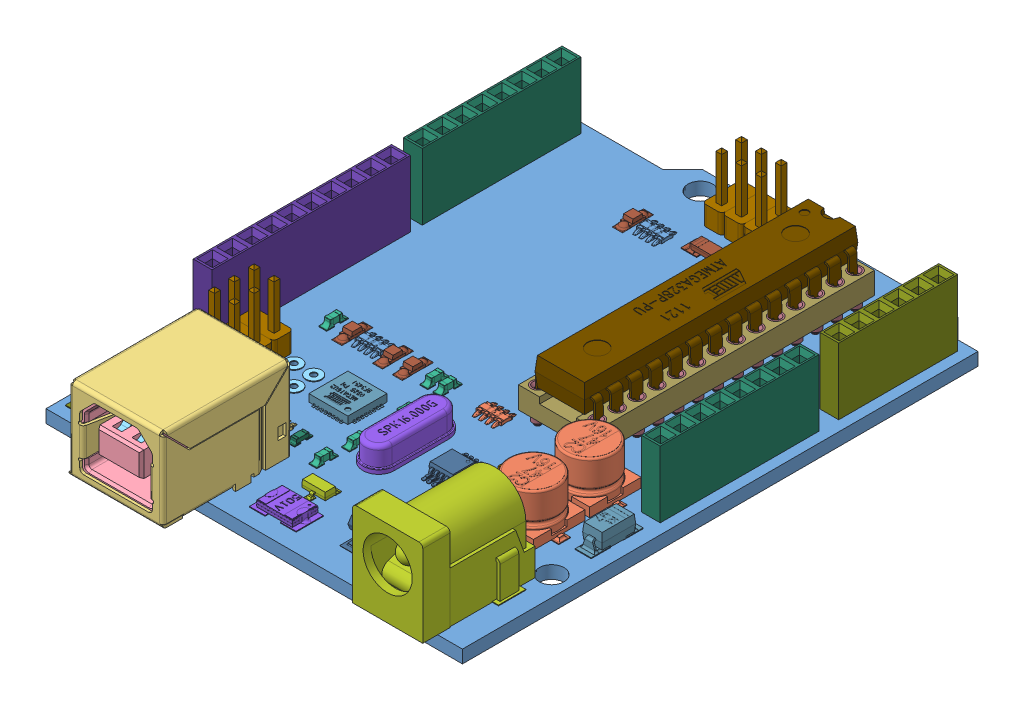
SolidWorks assembly arduino uno, configuration Default. Lengths in mm.
Overall size (53.34 15.25 74.93).
87 component instances, 35 part files, 133 mates.
Components (placement in the parent):
- unoboard blue-1: unoboard blue [Default] at origin size (53.34 1.65 68.58)
- 47uf CAP Dcase-1: 47uf CAP Dcase [Default] at (-9.4141 0 -18.4991) x (0 0 -1) z (1 0 0) size (6.6 5.81 8)
- USB type b-1: USB type b [Default] at (-38.02 0.43 6.35) size (14.34 15.2 16.5)
  - USB SHELL-1: USB SHELL [Default] at origin size (14.34 15.2 16.5)
  - USB core-1: USB core [Default] at origin size (11.3 10.68 15.75)
  - usb top contact-1: usb top contact [Default] at (1.25 6.09 -0.38) size (1 9.67 13.76)
  - usb btm contact-1: usb btm contact [Default] at (1.25 4.41 -0.38) size (1 6.84 11.76)
  - usb btm contact-2: usb btm contact [Default] at (-1.25 4.41 -0.38) size (1 6.84 11.76)
  - usb top contact-2: usb top contact [Default] at (-1.25 6.09 -0.38) size (1 9.67 13.76)
- power jack-1: power jack [Default] at (-7.675 0 1.905) size (11.2 15.2 15.9)
- 47uf CAP Dcase-2: 47uf CAP Dcase [Default] at (-9.4141 0 -25.7132) x (0 0 -1) z (1 0 0) size (6.6 5.81 8)
- crystal-1: crystal [Default] at (-26.162 0 -18.923) x (1 0 0) z (0 0 -1) size (4 5 11)
- 2pin_header__02-1: 2pin_header__02 [Default] at (-46.23 0 -15.75) size (5 11.75 2.54)
- nano - reg-1: nano - reg [Default] at (-17.399 0 -7.747) size (6.5 1.69 8.3)
- led-1: led [Default] at (-34.29 0 -27.94) x (0 0 1) z (-1 0 0) size (4 0.86 1.35)
- 2pin_header__02-2: 2pin_header__02 [Default] at (-30.43 0 -64.91) x (0 0 1) z (-1 0 0) size (5 11.75 2.54)
- dip28-1: dip28 [Default] at (-16.383 1.5 -46.355) x (0 0 -1) z (1 0 0) size (35.48 7.37 10.1)
  - dip28-1: dip28 [Default] at origin size (35.48 2.8 10.1)
  - dip socket pin-1: dip socket pin [Default] at (16.51 2.8 -3.81) size (1.7 7.37 1.7)
  - dip socket pin-2: dip socket pin [Default] at (16.51 2.8 3.81) size (1.7 7.37 1.7)
  - dip socket pin-3: dip socket pin [Default] at (13.97 2.8 -3.81) size (1.7 7.37 1.7)
  - dip socket pin-4: dip socket pin [Default] at (13.97 2.8 3.81) size (1.7 7.37 1.7)
  - dip socket pin-5: dip socket pin [Default] at (11.43 2.8 -3.81) size (1.7 7.37 1.7)
  - dip socket pin-6: dip socket pin [Default] at (11.43 2.8 3.81) size (1.7 7.37 1.7)
  - dip socket pin-7: dip socket pin [Default] at (8.89 2.8 -3.81) size (1.7 7.37 1.7)
  - dip socket pin-8: dip socket pin [Default] at (8.89 2.8 3.81) size (1.7 7.37 1.7)
  - dip socket pin-9: dip socket pin [Default] at (6.35 2.8 -3.81) size (1.7 7.37 1.7)
  - dip socket pin-10: dip socket pin [Default] at (6.35 2.8 3.81) size (1.7 7.37 1.7)
  - dip socket pin-11: dip socket pin [Default] at (3.81 2.8 -3.81) size (1.7 7.37 1.7)
  - dip socket pin-12: dip socket pin [Default] at (3.81 2.8 3.81) size (1.7 7.37 1.7)
  - dip socket pin-13: dip socket pin [Default] at (1.27 2.8 -3.81) size (1.7 7.37 1.7)
  - dip socket pin-14: dip socket pin [Default] at (1.27 2.8 3.81) size (1.7 7.37 1.7)
  - dip socket pin-15: dip socket pin [Default] at (-1.27 2.8 -3.81) size (1.7 7.37 1.7)
  - dip socket pin-16: dip socket pin [Default] at (-1.27 2.8 3.81) size (1.7 7.37 1.7)
  - dip socket pin-17: dip socket pin [Default] at (-3.81 2.8 -3.81) size (1.7 7.37 1.7)
  - dip socket pin-18: dip socket pin [Default] at (-3.81 2.8 3.81) size (1.7 7.37 1.7)
  - dip socket pin-19: dip socket pin [Default] at (-6.35 2.8 -3.81) size (1.7 7.37 1.7)
  - dip socket pin-20: dip socket pin [Default] at (-6.35 2.8 3.81) size (1.7 7.37 1.7)
  - dip socket pin-21: dip socket pin [Default] at (-8.89 2.8 -3.81) size (1.7 7.37 1.7)
  - dip socket pin-22: dip socket pin [Default] at (-8.89 2.8 3.81) size (1.7 7.37 1.7)
  - dip socket pin-23: dip socket pin [Default] at (-11.43 2.8 -3.81) size (1.7 7.37 1.7)
  - dip socket pin-24: dip socket pin [Default] at (-11.43 2.8 3.81) size (1.7 7.37 1.7)
  - dip socket pin-25: dip socket pin [Default] at (-13.97 2.8 -3.81) size (1.7 7.37 1.7)
  - dip socket pin-26: dip socket pin [Default] at (-13.97 2.8 3.81) size (1.7 7.37 1.7)
  - dip socket pin-27: dip socket pin [Default] at (-16.51 2.8 -3.81) size (1.7 7.37 1.7)
  - dip socket pin-28: dip socket pin [Default] at (-16.51 2.8 3.81) size (1.7 7.37 1.7)
- 2pin_header__02-3: 2pin_header__02 [Default] at (-27.89 0 -64.91) x (0 0 1) z (-1 0 0) size (5 11.75 2.54)
- 2pin_header__02-4: 2pin_header__02 [Default] at (-25.35 0 -64.91) x (0 0 1) z (-1 0 0) size (5 11.75 2.54)
- 2pin_header__02-5: 2pin_header__02 [Default] at (-46.23 0 -18.29) size (5 11.75 2.54)
- 2pin_header__02-6: 2pin_header__02 [Default] at (-46.23 0 -20.83) size (5 11.75 2.54)
- atmega16u2-1: atmega16u2 [Default] at (-34.671 0.06 -20) x (1 0 0) z (0 0 -1) size (5.5 1.01 5.5)
- led-2: led [Default] at (-36.83 0 -27.94) x (0 0 1) z (-1 0 0) size (4 0.86 1.35)
- led-3: led [Default] at (-42.037 0 -27.94) x (0 0 1) z (-1 0 0) size (4 0.86 1.35)
- led-4: led [Default] at (-36.576 0 -58.42) x (0 0 1) z (-1 0 0) size (4 0.86 1.35)
- 8 PORT HEADER-3: 8 PORT HEADER [Default] at (-50.8 0 -45.72) x (0 0 -1) z (1 0 0) size (20.32 10.51 2.41)
- 8 PORT HEADER-4: 8 PORT HEADER [Default] at (-2.54 0 -27.94) x (0 0 -1) z (1 0 0) size (20.32 10.51 2.41)
- 6 PORT HEADER-3: 6 PORT HEADER [Default] at (-2.54 0 -50.8) x (0 0 -1) z (1 0 0) size (15.24 10.51 2.41)
- 10 PORT HEADER-1: 10 PORT HEADER [Default] at (-50.8 0 -18.796) x (0 0 -1) z (1 0 0) size (25.4 10.51 2.41)
- ATMEL328P-1: ATMEL328P [Default] at (-16.383 4.3 -46.355) x (0 0 -1) z (1 0 0) size (35 7.27 7.87)
- 102 RESISTOR PACK-1: 102 RESISTOR PACK [Default] at (-33.782 0 -58.42) size (3.2 0.46 3)
- 102 RESISTOR PACK-2: 102 RESISTOR PACK [Default] at (-39.37 0 -27.94) size (3.2 0.46 3)
- 103 RESISTOR PACK-3: 103 RESISTOR PACK [Default] at (-23.876 0 -27.94) size (3.2 0.46 3)
- 220 RESISTOR PACK-1: 220 RESISTOR PACK [Default] at (-36.83 0 -12.827) size (3.2 0.46 3)
- 16mhz crystal - measured-1: 16mhz crystal - measured [Default] at (-24.892 0 -41.275) x (0 0 -1) z (1 0 0) size (3.4 0.8 2)
- PADS001-1: PADS001 [Default] at (-39.878 0.1 -18.288) x (-1 0 0) z (0 0 1) size (4.54 0.1 4.54)
- 603 cap on pad-1: 603 cap on pad [Default] at (-44.45 0 -27.94) x (0 0 -1) z (1 0 0) size (2.76 0.9 1.12)
- ssot3-1: ssot3 [Default] at (-26.5 0 -8.128) x (-1 0 0) z (0 0 -1) size (3 1.13 3.09)
- mf-msmf050-2-1: mf-msmf050-2 [Default] at (-26.5 0 -4.064) size (5.77 1.02 3.72)
- 603 cap on pad-2: 603 cap on pad [Default] at (-29.845 0 -27.94) x (0 0 -1) z (1 0 0) size (2.76 0.9 1.12)
- 603 cap on pad-3: 603 cap on pad [Default] at (-31.496 0 -27.94) x (0 0 -1) z (1 0 0) size (2.76 0.9 1.12)
- lmv358-1: lmv358 [Default] at (-15.24 0 -21.971) x (0 0 -1) z (1 0 0) size (3.7 1.4 2.9)
- 603 cap on pad-4: 603 cap on pad [Default] at (-15.24 0 -18.415) size (2.76 0.9 1.12)
- 603 cap on pad-5: 603 cap on pad [Default] at (-29.845 0 -12.065) x (0 0 1) z (-1 0 0) size (2.76 0.9 1.12)
- 603 cap on pad-6: 603 cap on pad [Default] at (-29.591 0 -22.352) x (0 0 1) z (-1 0 0) size (2.76 0.9 1.12)
- 603 cap on pad-7: 603 cap on pad [Default] at (-29.591 0 -16.002) x (0 0 1) z (-1 0 0) size (2.76 0.9 1.12)
- 603 cap on pad-8: 603 cap on pad [Default] at (-41.91 0 -12.7) x (0 0 1) z (-1 0 0) size (2.76 0.9 1.12)
- lp2985dgkr-1: lp2985dgkr [Default] at (-20.32 0 -19.05) x (0 0 -1) z (1 0 0) size (5.85 1.1 3)
- cd1206 diode-1: cd1206 diode [Default] at (-27.94 0 -59.436) x (0 0 -1) z (1 0 0) size (2.07 0.96 5)
- cd1206 diode-2: cd1206 diode [Default] at (-46.228 0 -13.081) x (0 0 1) z (-1 0 0) size (2.07 0.96 5)
- 603 resistor-1: 603 resistor [Default] at (-29.591 0 -19.05) x (0 0 1) z (-1 0 0) size (2.36 0.61 1.03)
- blm21-1: blm21 [Default] at (-45.085 0 -7.62) x (0 0 -1) z (1 0 0) size (2.76 0.95 1.32)
- m7 diode-1: m7 diode [Default] at (-2.794 0 -21.59) x (0 0 -1) z (1 0 0) size (6.66 2.35 2.5)
- MLC0603-1: MLC0603 [Default] at (-33.655 0 -12.827) x (0 0 -1) z (1 0 0) size (2.36 0.6 1.03)
- MLC0603-2: MLC0603 [Default] at (-39.37 0 -12.827) x (0 0 -1) z (1 0 0) size (2.36 0.6 1.03)
- RESET BUTTON-1: RESET BUTTON [Default] at (-49.403 0 -6.35) size (6.2 3.1 9.6)
  - RESET CORE-1: RESET CORE [Default] at (0 0.1 0) x (-1 0 0) z (0 0 -1) size (6.2 3.1 9.6)
  - RESET-1: RESET [Default] at (0 0.1 0) x (0 0 1) z (-1 0 0) size (7.3 2 6.2)
Mates (geometry in assembly coordinates):
- Distance1: distance = 1.905 mm aligned: plane of power jack-1 through (-7.675 0 1.905) normal (0 0 1); plane of unoboard blue-1 through (0 0 0) normal (0 0 1)
- Coincident2: coincident aligned: plane of unoboard blue-1 through (0 0 0) normal (0 1 0); plane of power jack-1 through (-7.675 0 1.905) normal (0 1 0)
- Coincident3: coincident anti-aligned: plane of unoboard blue-1 through (0 0 0) normal (0 1 0); plane of USB type b-1/USB core-1 through (-38.02 0 6.35) normal (0 -1 0)
- Distance2: distance = 6.35 mm aligned: plane of USB type b-1/USB SHELL-1 through (-38.02 0.43 6.35) normal (0 0 1); plane of unoboard blue-1 through (0 0 0) normal (0 0 1)
- Coincident5: coincident aligned: plane of unoboard blue-1 through (0 0 0) normal (0 1 0); plane of 47uf CAP Dcase-1 through (-9.4141 0 -18.4991) normal (0 1 0)
- Parallel1: parallel anti-aligned: plane of unoboard blue-1 through (0 0 0) normal (0 0 1); plane of 47uf CAP Dcase-1 through (-9.4141 0 -18.4991) normal (0 0 -1)
- Coincident7: coincident aligned: plane of 47uf CAP Dcase-1 through (-6.1141 1.5 -15.1991) normal (1 0 0); plane of 47uf CAP Dcase-2 through (-6.1141 1.5 -22.4132) normal (1 0 0)
- Coincident8: coincident anti-aligned: plane of unoboard blue-1 through (0 0 0) normal (0 1 0); plane of 47uf CAP Dcase-2 through (-8.1891 0 -25.7132) normal (0 -1 0)
- Distance3: distance = 3.175 mm aligned: plane of power jack-1 through (-3.175 10.5 -1.595) normal (1 0 0); plane of unoboard blue-1 through (0 -1.65 0) normal (1 0 0)
- Distance4: distance = 32 mm aligned: plane of USB type b-1/USB SHELL-1 through (-32 0.43 6.35) normal (1 0 0); plane of unoboard blue-1 through (0 -1.65 0) normal (1 0 0)
- Coincident11: coincident anti-aligned: plane of unoboard blue-1 through (0 0 0) normal (0 1 0); plane of crystal-1 through (-26.162 0 -22.423) normal (0 -1 0)
- Concentric1: concentric aligned: cylinder of unoboard blue-1 through (-26.162 -10 -16.383) axis (0 1 0) radius 0.5; cylinder of crystal-1 through (-26.162 -2 -16.383) axis (0 1 0) radius 0.4
- Concentric2: concentric aligned: cylinder of unoboard blue-1 through (-26.162 -10 -21.463) axis (0 1 0) radius 0.5; cylinder of crystal-1 through (-26.162 -2 -21.463) axis (0 1 0) radius 0.4
- Coincident12: coincident anti-aligned: plane of unoboard blue-1 through (0 0 0) normal (0 1 0); plane of 2pin_header__02-1 through (-44.23 0 -14.98) normal (0 -1 0)
- Distance5: distance = 15.75 mm aligned: plane of 2pin_header__02-1 through (-46.23 0 -15.75) normal (0 0 1); plane of assembly through (0 0 0) normal (0 0 1)
- Distance6: distance = 46.23 mm aligned: plane of 2pin_header__02-1 through (-46.23 0 -15.75) normal (1 0 0); plane of assembly through (0 0 0) normal (1 0 0)
- Coincident15: coincident anti-aligned: plane of unoboard blue-1 through (0 0 0) normal (0 1 0); plane of 2pin_header__02-2 through (-31.2 0 -62.91) normal (0 -1 0)
- Distance7: distance = 64.91 mm aligned: plane of 2pin_header__02-2 through (-30.43 0 -64.91) normal (0 0 1); plane of assembly through (0 0 0) normal (0 0 1)
- Distance8: distance = 30.43 mm anti-aligned: plane of 2pin_header__02-2 through (-30.43 0 -64.91) normal (-1 0 0); plane of assembly through (0 0 0) normal (1 0 0)
- Coincident19: coincident anti-aligned: plane of unoboard blue-1 through (0 0 0) normal (0 1 0); plane of nano - reg-1 through (-17.399 0 -7.747) normal (0 -1 0)
- Concentric3: concentric aligned: cylinder of unoboard blue-1 through (-20.193 -10 -62.865) axis (0 1 0) radius 0.4; cylinder of dip28-1/dip socket pin-1 through (-20.193 33.2926 -62.865) axis (0 1 0) radius 0.25
- Concentric4: concentric aligned: cylinder of unoboard blue-1 through (-12.573 -10 -29.845) axis (0 1 0) radius 0.4; cylinder of dip28-1/dip socket pin-28 through (-12.573 33.2926 -29.845) axis (0 1 0) radius 0.25
- Distance9: distance = 1.5 mm anti-aligned: plane of dip28-1/dip28-1 through (-11.333 1.5 -64.095) normal (0 -1 0); plane of unoboard blue-1 through (0 0 0) normal (0 1 0)
- Coincident21: coincident anti-aligned: plane of unoboard blue-1 through (0 0 0) normal (0 1 0); plane of atmega16u2-1 through (-34.671 0 -20) normal (0 -1 0)
- Distance10: distance = 20 mm anti-aligned: plane of atmega16u2-1 through (-34.671 0.06 -20) normal (0 0 -1); plane of unoboard blue-1 through (0 0 0) normal (0 0 1)
- Distance11: distance = 34.671 mm aligned: plane of atmega16u2-1 through (-34.671 0.06 -20) normal (1 0 0); plane of unoboard blue-1 through (0 0 0) normal (1 0 0)
- Coincident25: coincident anti-aligned: plane of unoboard blue-1 through (0 0 0) normal (0 1 0); plane of led-1 through (-34.29 0 -28.94) normal (0 -1 0)
- Distance12: distance = 34.29 mm anti-aligned: plane of led-1 through (-34.29 0 -27.94) normal (-1 0 0); plane of unoboard blue-1 through (0 0 0) normal (1 0 0)
- Distance13: distance = 27.94 mm aligned: plane of led-1 through (-34.29 0 -27.94) normal (0 0 1); plane of unoboard blue-1 through (0 0 0) normal (0 0 1)
- Coincident28: coincident aligned: plane of led-2 through (-36.83 0 -28.94) normal (0 -1 0); plane of led-3 through (-42.037 0 -28.94) normal (0 -1 0)
- Coincident29: coincident aligned: plane of led-1 through (-34.29 0 -27.94) normal (0 0 1); plane of led-2 through (-36.83 0 -27.94) normal (0 0 1)
- Coincident30: coincident aligned: plane of led-1 through (-34.29 0 -27.94) normal (0 0 1); plane of led-3 through (-42.037 0 -27.94) normal (0 0 1)
- Distance14: distance = 2.54 mm aligned: plane of led-2 through (-36.83 0 -27.94) normal (-1 0 0); plane of led-1 through (-34.29 0 -27.94) normal (-1 0 0)
- Coincident32: coincident anti-aligned: plane of unoboard blue-1 through (0 0 0) normal (0 1 0); plane of led-2 through (-36.83 0 -28.94) normal (0 -1 0)
- Distance15: distance = 42.037 mm anti-aligned: plane of led-3 through (-42.037 0 -27.94) normal (-1 0 0); plane of unoboard blue-1 through (0 0 0) normal (1 0 0)
- Coincident34: coincident anti-aligned: plane of unoboard blue-1 through (0 0 0) normal (0 1 0); plane of led-4 through (-36.576 0 -59.42) normal (0 -1 0)
- Distance16: distance = 36.576 mm anti-aligned: plane of led-4 through (-36.576 0 -58.42) normal (-1 0 0); plane of unoboard blue-1 through (0 0 0) normal (1 0 0)
- Distance17: distance = 58.42 mm aligned: plane of led-4 through (-36.576 0 -58.42) normal (0 0 1); plane of unoboard blue-1 through (0 0 0) normal (0 0 1)
- Coincident37: coincident aligned: plane of unoboard blue-1 through (0 0 0) normal (0 1 0); plane of 8 PORT HEADER-4 through (-2.54 0 -27.94) normal (0 1 0)
- Coincident38: coincident aligned: plane of unoboard blue-1 through (0 0 0) normal (0 1 0); plane of 8 PORT HEADER-3 through (-50.8 0 -45.72) normal (0 1 0)
- Parallel2: parallel aligned: plane of unoboard blue-1 through (0 0 0) normal (1 0 0); plane of 8 PORT HEADER-4 through (-2.54 0 -27.94) normal (1 0 0)
- Parallel3: parallel aligned: plane of unoboard blue-1 through (0 0 0) normal (1 0 0); plane of 8 PORT HEADER-3 through (-50.8 0 -45.72) normal (1 0 0)
- Concentric5: concentric aligned: cylinder of unoboard blue-1 through (-2.54 -1.65 -27.94) axis (0 1 0) radius 0.4; line of 8 PORT HEADER-4 through (-2.54 -2.5255 -27.94) axis (0 1 0)
- Concentric6: concentric aligned: cylinder of unoboard blue-1 through (-50.8 -1.65 -45.72) axis (0 1 0) radius 0.4; line of 8 PORT HEADER-3 through (-50.8 -2.5255 -45.72) axis (0 1 0)
- Coincident43: coincident aligned: plane of unoboard blue-1 through (0 0 0) normal (0 1 0); plane of 10 PORT HEADER-1 through (-50.8 0 -18.796) normal (0 1 0)
- Coincident44: coincident aligned: plane of unoboard blue-1 through (0 0 0) normal (0 1 0); plane of 6 PORT HEADER-3 through (-2.54 0 -50.8) normal (0 1 0)
- Parallel4: parallel aligned: plane of unoboard blue-1 through (0 0 0) normal (1 0 0); plane of 6 PORT HEADER-3 through (-2.54 0 -50.8) normal (1 0 0)
- Parallel5: parallel aligned: plane of unoboard blue-1 through (0 0 0) normal (1 0 0); plane of 10 PORT HEADER-1 through (-50.8 0 -18.796) normal (1 0 0)
- Concentric7: concentric aligned: cylinder of unoboard blue-1 through (-50.8 -1.65 -18.796) axis (0 1 0) radius 0.4; line of 10 PORT HEADER-1 through (-50.8 -2.5255 -18.796) axis (0 1 0)
- Concentric9: concentric aligned: cylinder of unoboard blue-1 through (-2.54 -1.65 -50.8) axis (0 1 0) radius 0.4; line of 6 PORT HEADER-3 through (-2.54 -2.5255 -50.8) axis (0 1 0)
- Coincident50: coincident aligned: plane of dip28-1/dip28-1 through (-16.383 1.5 -46.355) normal (0 0 -1); plane of ATMEL328P-1 through (-16.383 4.3 -46.355) normal (0 0 -1)
- Coincident51: coincident aligned: plane of dip28-1 through (-16.383 1.5 -46.355) normal (1 0 0); plane of ATMEL328P-1 through (-16.383 4.3 -46.355) normal (1 0 0)
- Coincident52: coincident aligned: plane of dip28-1/dip28-1 through (-11.333 4.3 -64.095) normal (0 1 0); plane of ATMEL328P-1 through (-16.383 4.3 -46.355) normal (0 1 0)
- Distance18: distance = 7.747 mm: plane of nano - reg-1 through (-17.399 0 -7.747) normal (0 0 1); line of unoboard blue-1 through (0 53.34 -53.34) axis (0 0 1)
- Distance19: distance = 17.399 mm aligned: plane of nano - reg-1 through (-17.399 0 -7.747) normal (1 0 0); plane of unoboard blue-1 through (0 0 0) normal (1 0 0)
- Coincident55: coincident anti-aligned: plane of unoboard blue-1 through (0 0 0) normal (0 1 0); plane of 102 RESISTOR PACK-1 through (-33.982 0 -59.12) normal (0 -1 0)
- Distance20: distance = 33.782 mm aligned: plane of 102 RESISTOR PACK-1 through (-33.782 0 -58.42) normal (1 0 0); plane of unoboard blue-1 through (0 0 0) normal (1 0 0)
- Distance21: distance = 58.42 mm aligned: plane of 102 RESISTOR PACK-1 through (-33.782 0 -58.42) normal (0 0 1); plane of unoboard blue-1 through (0 0 0) normal (0 0 1)
- Coincident58: coincident aligned: plane of 102 RESISTOR PACK-2 through (-39.37 0 -27.94) normal (0 1 0); plane of 103 RESISTOR PACK-3 through (-23.876 0 -27.94) normal (0 1 0)
- Coincident59: coincident aligned: plane of unoboard blue-1 through (0 0 0) normal (0 1 0); plane of 103 RESISTOR PACK-3 through (-23.876 0 -27.94) normal (0 1 0)
- Coincident60: coincident aligned: plane of 102 RESISTOR PACK-2 through (-39.37 0 -27.94) normal (0 0 1); plane of 103 RESISTOR PACK-3 through (-23.876 0 -27.94) normal (0 0 1)
- Distance22: distance = 23.876 mm aligned: plane of 103 RESISTOR PACK-3 through (-23.876 0 -27.94) normal (1 0 0); plane of unoboard blue-1 through (0 0 0) normal (1 0 0)
- Distance23: distance = 39.37 mm aligned: plane of 102 RESISTOR PACK-2 through (-39.37 0 -27.94) normal (1 0 0); plane of unoboard blue-1 through (0 0 0) normal (1 0 0)
- Distance24: distance = 27.94 mm aligned: plane of 102 RESISTOR PACK-2 through (-39.37 0 -27.94) normal (0 0 1); plane of unoboard blue-1 through (0 0 0) normal (0 0 1)
- Distance25: distance = 12.827 mm aligned: plane of 220 RESISTOR PACK-1 through (-36.83 0 -12.827) normal (0 0 1); plane of unoboard blue-1 through (0 0 0) normal (0 0 1)
- Distance26: distance = 36.83 mm aligned: plane of 220 RESISTOR PACK-1 through (-36.83 0 -12.827) normal (1 0 0); plane of unoboard blue-1 through (0 0 0) normal (1 0 0)
- Coincident66: coincident aligned: plane of unoboard blue-1 through (0 0 0) normal (0 1 0); plane of 220 RESISTOR PACK-1 through (-36.83 0 -12.827) normal (0 1 0)
- Coincident67: coincident anti-aligned: plane of unoboard blue-1 through (0 0 0) normal (0 1 0); plane of 16mhz crystal - measured-1 through (-24.892 0 -41.275) normal (0 -1 0)
- Distance27: distance = 41.275 mm anti-aligned: plane of 16mhz crystal - measured-1 through (-24.892 0 -41.275) normal (0 0 -1); plane of unoboard blue-1 through (0 0 0) normal (0 0 1)
- Distance28: distance = 24.892 mm aligned: plane of 16mhz crystal - measured-1 through (-24.892 0 -41.275) normal (1 0 0); plane of unoboard blue-1 through (0 0 0) normal (1 0 0)
- Coincident70: coincident anti-aligned: plane of unoboard blue-1 through (0 0 0) normal (0 1 0); plane of PADS001-1 through (-42.418 0 -18.288) normal (0 -1 0)
- Distance29: distance = 18.288 mm aligned: plane of PADS001-1 through (-39.878 0.1 -18.288) normal (0 0 1); plane of unoboard blue-1 through (0 0 0) normal (0 0 1)
- Distance30: distance = 39.878 mm anti-aligned: plane of PADS001-1 through (-39.878 0.1 -18.288) normal (-1 0 0); plane of unoboard blue-1 through (0 0 0) normal (1 0 0)
- Distance31: distance = 4.064 mm aligned: plane of mf-msmf050-2-1 through (-26.5 0 -4.064) normal (0 0 1); plane of unoboard blue-1 through (0 0 0) normal (0 0 1)
- Distance32: distance = 26.5 mm aligned: plane of mf-msmf050-2-1 through (-26.5 0 -4.064) normal (1 0 0); plane of unoboard blue-1 through (0 0 0) normal (1 0 0)
- Coincident72: coincident aligned: plane of unoboard blue-1 through (0 0 0) normal (0 1 0); plane of mf-msmf050-2-1 through (-26.5 0 -4.064) normal (0 1 0)
- Distance33: distance = 8.128 mm anti-aligned: plane of unoboard blue-1 through (0 0 0) normal (0 0 1); plane of ssot3-1 through (-26.5 0 -8.128) normal (0 0 -1)
- Coincident74: coincident anti-aligned: plane of ssot3-1 through (-26.5 0 -8.128) normal (-1 0 0); plane of mf-msmf050-2-1 through (-26.5 0 -4.064) normal (1 0 0)
- Coincident75: coincident aligned: plane of unoboard blue-1 through (0 0 0) normal (0 1 0); plane of ssot3-1 through (-26.5 0 -8.128) normal (0 1 0)
- Coincident76: coincident anti-aligned: plane of led-1 through (-34.29 0 -27.94) normal (0 0 1); plane of 603 cap on pad-1 through (-44.45 0 -27.94) normal (0 0 -1)
- Coincident77: coincident aligned: plane of unoboard blue-1 through (0 0 0) normal (0 1 0); plane of 603 cap on pad-1 through (-44.45 0 -27.94) normal (0 1 0)
- Distance34: distance = 44.45 mm aligned: plane of 603 cap on pad-1 through (-44.45 0 -27.94) normal (1 0 0); plane of unoboard blue-1 through (0 0 0) normal (1 0 0)
- Coincident79: coincident aligned: plane of 603 cap on pad-2 through (-29.845 0 -27.94) normal (0 1 0); plane of 603 cap on pad-3 through (-31.496 0 -27.94) normal (0 1 0)
- Coincident80: coincident aligned: plane of 603 cap on pad-2 through (-29.845 0 -27.94) normal (0 0 -1); plane of 603 cap on pad-3 through (-31.496 0 -27.94) normal (0 0 -1)
- Coincident81: coincident aligned: plane of unoboard blue-1 through (0 0 0) normal (0 1 0); plane of 603 cap on pad-2 through (-29.845 0 -27.94) normal (0 1 0)
- Coincident82: coincident aligned: plane of 603 cap on pad-1 through (-44.45 0 -27.94) normal (0 0 -1); plane of 603 cap on pad-2 through (-29.845 0 -27.94) normal (0 0 -1)
- Distance36: distance = 29.845 mm aligned: plane of 603 cap on pad-2 through (-29.845 0 -27.94) normal (1 0 0); plane of unoboard blue-1 through (0 0 0) normal (1 0 0)
- Distance37: distance = 31.496 mm aligned: plane of 603 cap on pad-3 through (-31.496 0 -27.94) normal (1 0 0); plane of unoboard blue-1 through (0 0 0) normal (1 0 0)
- Distance38: distance = 15.24 mm aligned: plane of unoboard blue-1 through (0 0 0) normal (1 0 0); plane of lmv358-1 through (-15.24 0 -21.971) normal (1 0 0)
- Distance39: distance = 21.971 mm anti-aligned: plane of lmv358-1 through (-15.24 0 -21.971) normal (0 0 -1); plane of unoboard blue-1 through (0 0 0) normal (0 0 1)
- Coincident88: coincident aligned: plane of unoboard blue-1 through (0 0 0) normal (0 1 0); plane of lmv358-1 through (-15.24 0 -21.971) normal (0 1 0)
- Distance40: distance = 18.415 mm aligned: plane of 603 cap on pad-4 through (-15.24 0 -18.415) normal (0 0 1); plane of unoboard blue-1 through (0 0 0) normal (0 0 1)
- Distance41: distance = 15.24 mm aligned: plane of 603 cap on pad-4 through (-15.24 0 -18.415) normal (1 0 0); plane of unoboard blue-1 through (0 0 0) normal (1 0 0)
- Coincident91: coincident aligned: plane of unoboard blue-1 through (0 0 0) normal (0 1 0); plane of 603 cap on pad-4 through (-15.24 0 -18.415) normal (0 1 0)
- Coincident92: coincident aligned: plane of unoboard blue-1 through (0 0 0) normal (0 1 0); plane of 603 cap on pad-7 through (-29.591 0 -16.002) normal (0 1 0)
- Coincident93: coincident aligned: plane of unoboard blue-1 through (0 0 0) normal (0 1 0); plane of 603 cap on pad-6 through (-29.591 0 -22.352) normal (0 1 0)
- Coincident94: coincident aligned: plane of 603 cap on pad-5 through (-29.845 0 -12.065) normal (0 1 0); plane of unoboard blue-1 through (0 0 0) normal (0 1 0)
- Coincident95: coincident aligned: plane of 603 cap on pad-8 through (-41.91 0 -12.7) normal (0 1 0); plane of unoboard blue-1 through (0 0 0) normal (0 1 0)
- Coincident96: coincident aligned: plane of 603 cap on pad-7 through (-29.591 0 -16.002) normal (-1 0 0); plane of 603 cap on pad-6 through (-29.591 0 -22.352) normal (-1 0 0)
- Distance42: distance = 29.591 mm anti-aligned: plane of 603 cap on pad-7 through (-29.591 0 -16.002) normal (-1 0 0); plane of unoboard blue-1 through (0 0 0) normal (1 0 0)
- Distance43: distance = 22.352 mm: plane of 603 cap on pad-6 through (-29.591 0 -22.352) normal (0 0 1); line of unoboard blue-1 through (0 53.34 -53.34) axis (0 0 1)
- Distance44: distance = 16.002 mm aligned: plane of 603 cap on pad-7 through (-29.591 0 -16.002) normal (0 0 1); plane of unoboard blue-1 through (0 0 0) normal (0 0 1)
- Distance45: distance = 29.845 mm anti-aligned: plane of 603 cap on pad-5 through (-29.845 0 -12.065) normal (-1 0 0); plane of unoboard blue-1 through (0 0 0) normal (1 0 0)
- Distance46: distance = 12.065 mm aligned: plane of 603 cap on pad-5 through (-29.845 0 -12.065) normal (0 0 1); plane of unoboard blue-1 through (0 0 0) normal (0 0 1)
- Distance47: distance = 41.91 mm anti-aligned: plane of 603 cap on pad-8 through (-41.91 0 -12.7) normal (-1 0 0); plane of unoboard blue-1 through (0 0 0) normal (1 0 0)
- Distance48: distance = 12.7 mm aligned: plane of 603 cap on pad-8 through (-41.91 0 -12.7) normal (0 0 1); plane of unoboard blue-1 through (0 0 0) normal (0 0 1)
- Distance49: distance = 20.32 mm aligned: plane of lp2985dgkr-1 through (-20.32 0 -19.05) normal (1 0 0); plane of unoboard blue-1 through (0 0 0) normal (1 0 0)
- Distance50: distance = 19.05 mm anti-aligned: plane of lp2985dgkr-1 through (-20.32 0 -19.05) normal (0 0 -1); plane of unoboard blue-1 through (0 0 0) normal (0 0 1)
- Coincident99: coincident aligned: plane of unoboard blue-1 through (0 0 0) normal (0 1 0); plane of lp2985dgkr-1 through (-20.32 0 -19.05) normal (0 1 0)
- Distance51: distance = 27.94 mm aligned: plane of cd1206 diode-1 through (-27.94 0 -59.436) normal (1 0 0); plane of unoboard blue-1 through (0 0 0) normal (1 0 0)
- Distance52: distance = 59.436 mm anti-aligned: plane of cd1206 diode-1 through (-27.94 0 -59.436) normal (0 0 -1); plane of unoboard blue-1 through (0 0 0) normal (0 0 1)
- Coincident102: coincident aligned: plane of unoboard blue-1 through (0 0 0) normal (0 1 0); plane of cd1206 diode-1 through (-27.94 0 -59.436) normal (0 1 0)
- Distance53: distance = 46.228 mm anti-aligned: plane of cd1206 diode-2 through (-46.228 0 -13.081) normal (-1 0 0); plane of unoboard blue-1 through (0 0 0) normal (1 0 0)
- Distance54: distance = 13.081 mm aligned: plane of unoboard blue-1 through (0 0 0) normal (0 0 1); plane of cd1206 diode-2 through (-46.228 0 -13.081) normal (0 0 1)
- Coincident105: coincident aligned: plane of unoboard blue-1 through (0 0 0) normal (0 1 0); plane of cd1206 diode-2 through (-46.228 0 -13.081) normal (0 1 0)
- Distance55: distance = 29.591 mm anti-aligned: plane of 603 resistor-1 through (-29.591 0 -19.05) normal (-1 0 0); plane of unoboard blue-1 through (0 0 0) normal (1 0 0)
- Distance56: distance = 19.05 mm aligned: plane of 603 resistor-1 through (-29.591 0 -19.05) normal (0 0 1); plane of unoboard blue-1 through (0 0 0) normal (0 0 1)
- Coincident108: coincident aligned: plane of unoboard blue-1 through (0 0 0) normal (0 1 0); plane of 603 resistor-1 through (-29.591 0 -19.05) normal (0 1 0)
- Distance57: distance = 7.62 mm anti-aligned: plane of blm21-1 through (-45.085 0 -7.62) normal (0 0 -1); plane of unoboard blue-1 through (0 0 0) normal (0 0 1)
- Distance58: distance = 45.085 mm aligned: plane of blm21-1 through (-45.085 0 -7.62) normal (1 0 0); plane of unoboard blue-1 through (0 0 0) normal (1 0 0)
- Distance59: distance = 21.59 mm anti-aligned: plane of m7 diode-1 through (-2.794 0 -21.59) normal (0 0 -1); plane of unoboard blue-1 through (0 0 0) normal (0 0 1)
- Distance60: distance = 2.794 mm aligned: plane of m7 diode-1 through (-2.794 0 -21.59) normal (1 0 0); plane of unoboard blue-1 through (0 0 0) normal (1 0 0)
- Coincident113: coincident aligned: plane of unoboard blue-1 through (0 0 0) normal (0 1 0); plane of m7 diode-1 through (-2.794 0 -21.59) normal (0 1 0)
- Coincident114: coincident anti-aligned: plane of 220 RESISTOR PACK-1 through (-36.83 0 -12.827) normal (0 0 1); plane of MLC0603-1 through (-33.655 0 -12.827) normal (0 0 -1)
- Distance61: distance = 33.655 mm aligned: plane of MLC0603-1 through (-33.655 0 -12.827) normal (1 0 0); plane of unoboard blue-1 through (0 0 0) normal (1 0 0)
- Coincident115: coincident aligned: plane of unoboard blue-1 through (0 0 0) normal (0 1 0); plane of MLC0603-1 through (-33.655 0 -12.827) normal (0 1 0)
- Coincident116: coincident aligned: plane of unoboard blue-1 through (0 0 0) normal (0 1 0); plane of blm21-1 through (-45.085 0 -7.62) normal (0 1 0)
- Coincident117: coincident anti-aligned: plane of 220 RESISTOR PACK-1 through (-36.83 0 -12.827) normal (0 0 1); plane of MLC0603-2 through (-39.37 0 -12.827) normal (0 0 -1)
- Coincident118: coincident aligned: plane of unoboard blue-1 through (0 0 0) normal (0 1 0); plane of MLC0603-2 through (-39.37 0 -12.827) normal (0 1 0)
- Distance62: distance = 39.37 mm aligned: plane of MLC0603-2 through (-39.37 0 -12.827) normal (1 0 0); plane of unoboard blue-1 through (0 0 0) normal (1 0 0)
- Distance63: distance = 49.403 mm aligned: plane of RESET BUTTON-1 through (-49.403 0 -6.35) normal (1 0 0); plane of unoboard blue-1 through (0 0 0) normal (1 0 0)
- Distance64: distance = 6.35 mm aligned: plane of RESET BUTTON-1; plane of unoboard blue-1 through (0 0 0) normal (0 0 1)
- Coincident122: coincident aligned: plane of unoboard blue-1 through (0 0 0) normal (0 1 0); plane of RESET BUTTON-1 through (-49.403 0 -6.35) normal (0 1 0)
